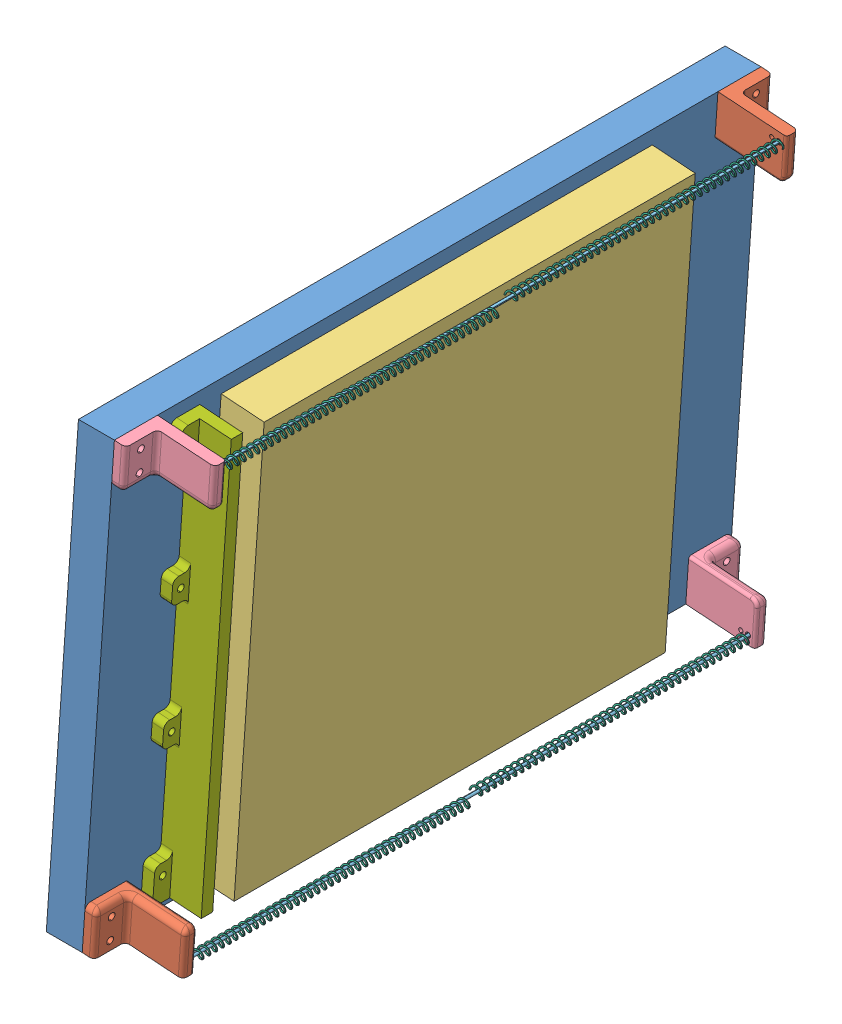
SolidWorks assembly R-03-01, configuration Default. Lengths in mm.
Overall size (95.68 323.35 450.01).
14 component instances, 7 part files, 0 mates.
Components (placement in the parent):
- Radiateur.STEP-1: Radiateur.STEP [Default] at origin size (95.68 323.35 450.01)
  - Mur_largeur.STEP-1: Mur_largeur.STEP [Default] at (-64.9032 -140.3514 -216.6004) size (47.38 320 450)
  - braquetterad2.STEP-1: braquetterad2.STEP [Default] at (-39.9032 -140.3514 233.3996) x (0 0 -1) z (-0.069756 -0.997564 0) size (30 48 30)
  - 05-Radiateur.STEP-1: 05-Radiateur.STEP [Default] at (-9.2242 -131.689 158.3996) x (0.069756 0.997564 0) z (0 0 1) size (300 30 300)
  - braquetterad1.STEP-1: braquetterad1.STEP [Default] at (-19.6193 149.7217 233.3996) x (0 0 -1) z (-0.069756 -0.997564 0) size (30 48 30)
  - braquetterad2.STEP-2: braquetterad2.STEP [Default] at (-17.5266 179.6486 -216.6004) x (0 0 1) z (0.069756 0.997564 0) size (30 48 30)
  - braquetterad1.STEP-2: braquetterad1.STEP [Default] at (-37.8105 -110.4245 -216.6004) x (0 0 1) z (0.069756 0.997564 0) size (30 48 30)
  - tigerad.STEP-1: tigerad.STEP [Default] at (24.9501 170.6637 -191.6004) x (-0.267506 0.963556 0) z (0.963556 0.267506 0) size (2 400 2)
  - tigerad.STEP-2: tigerad.STEP [Default] at (3.4106 -137.3656 208.3996) x (1 0 0) z (0 1 0) size (2 400 2)
  - Springs.STEP-1: Springs.STEP [Default] at (0.7048 -136.4477 4.1759) x (1 0 0) z (0 0.999962 -0.008727) size (7 191 8.08)
  - Springs.STEP-2: Springs.STEP [Default] at (22.024 170.9453 1.098) x (1 0 0) z (0 0.999962 -0.008727) size (7 191 8.08)
  - Springs.STEP-3: Springs.STEP [Default] at (24.2732 170.9212 201.9899) x (1 0 0) z (0 0.999962 -0.008727) size (7 191 8.08)
  - Springs.STEP-4: Springs.STEP [Default] at (2.2292 -136.5481 199.8891) x (1 0 0) z (0 0.999962 -0.008727) size (7 191 8.08)
  - rightshield.STEP-1: rightshield.STEP [Default] at (-39.0719 -128.4631 173.3565) x (0.997564 -0.069756 0) z (-0.069756 -0.997564 0) size (30 20 300)
